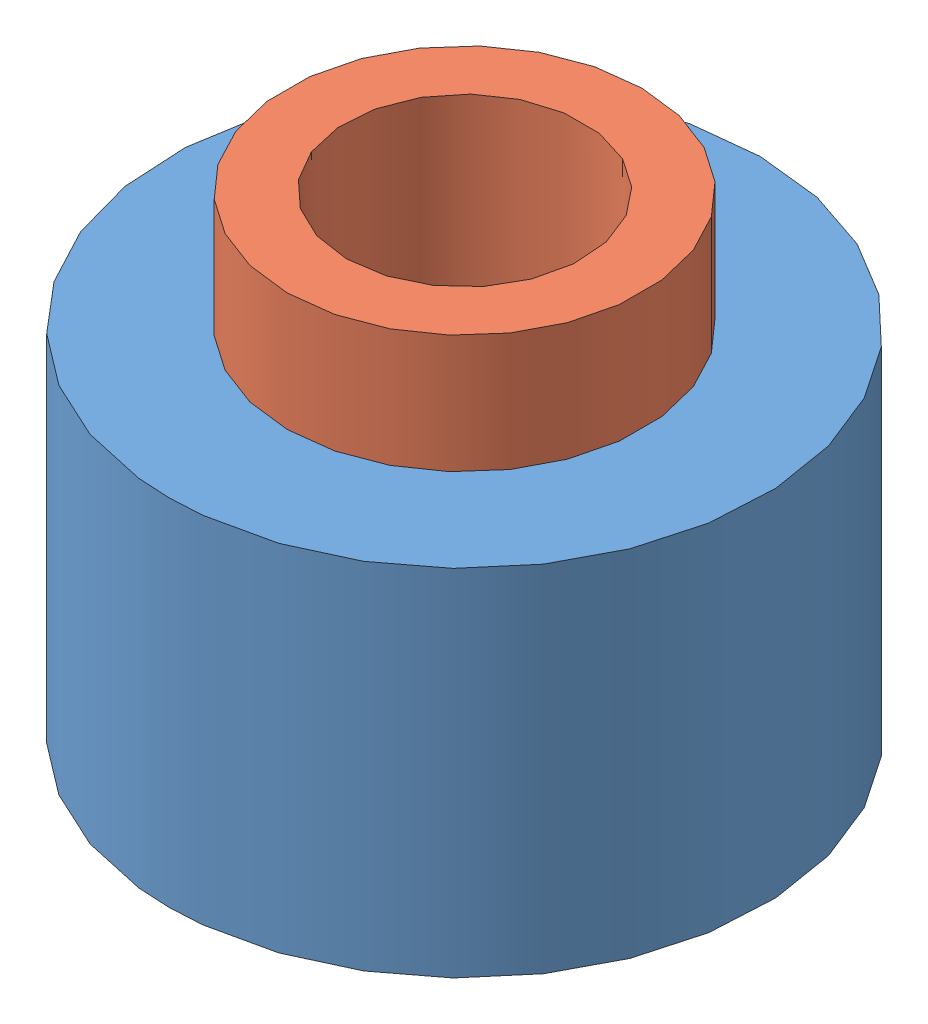
SolidWorks assembly Assemblage1, configuration Default. Lengths in mm.
Overall size (25 20 25).
2 component instances, 2 part files, 2 mates.
Components (placement in the parent):
- Rouleau_D25_H15-1: Rouleau_D25_H15 [Default] at (-6.5011 -2.8091 0.2436) size (25 15 25)
- Support_Rouleau_D15_H20-1: Support_Rouleau_D15_H20 [Default] at (-6.5011 12.1909 0.2436) size (15 20 15)
Mates (geometry in assembly coordinates):
- Coaxiale1: concentric: cylinder of Rouleau_D25_H15-1; cylinder of ?
- Coïncidente1: coincident anti-aligned: plane of Rouleau_D25_H15-1 through (-6.5011 12.1909 0.2436) normal (0 1 0); plane of ? through (-6.5011 34.88 0.2436) normal (0 -1 0)
